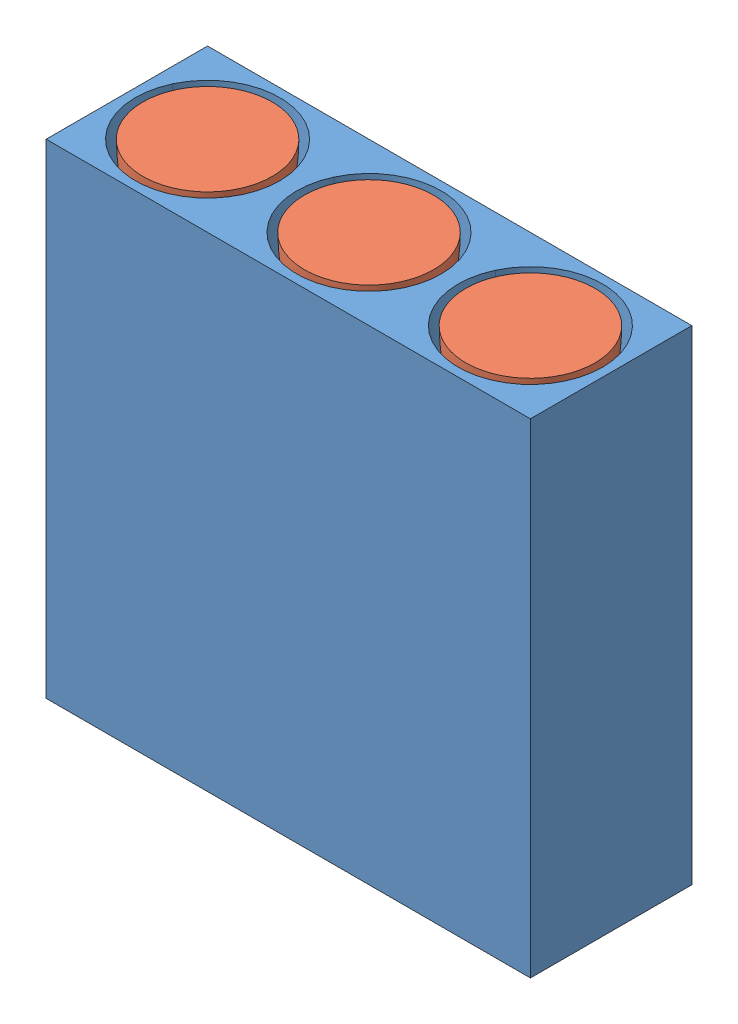
SolidWorks assembly NarrowerSpace, configuration Default. Lengths in mm.
Overall size (15 15 5.31).
4 component instances, 2 part files, 1 mates.
Components (placement in the parent):
- cone_base_tall_2-1: cone_base_tall_2 [Default] at origin size (15 15 5.31)
- convex_cone-1: convex_cone [Default] at (5 18.1 2.5) x (-1 0 0) z (0 0 1) size (4 15 4)
- convex_cone-2: convex_cone [Default] at (0 18.1 2.5) x (-1 0 0) z (0 0 1) size (4 15 4)
- convex_cone-3: convex_cone [Default] at (-5 18.1 2.5) x (-1 0 0) z (0 0 1) size (4 15 4)
Mates (geometry in assembly coordinates):
- Coincident2: coincident aligned: plane of cone_base_tall_2-1 through (-7.5 18.1 5) normal (0 1 0); plane of convex_cone-1 through (5 18.1 2.5) normal (0 1 0)
